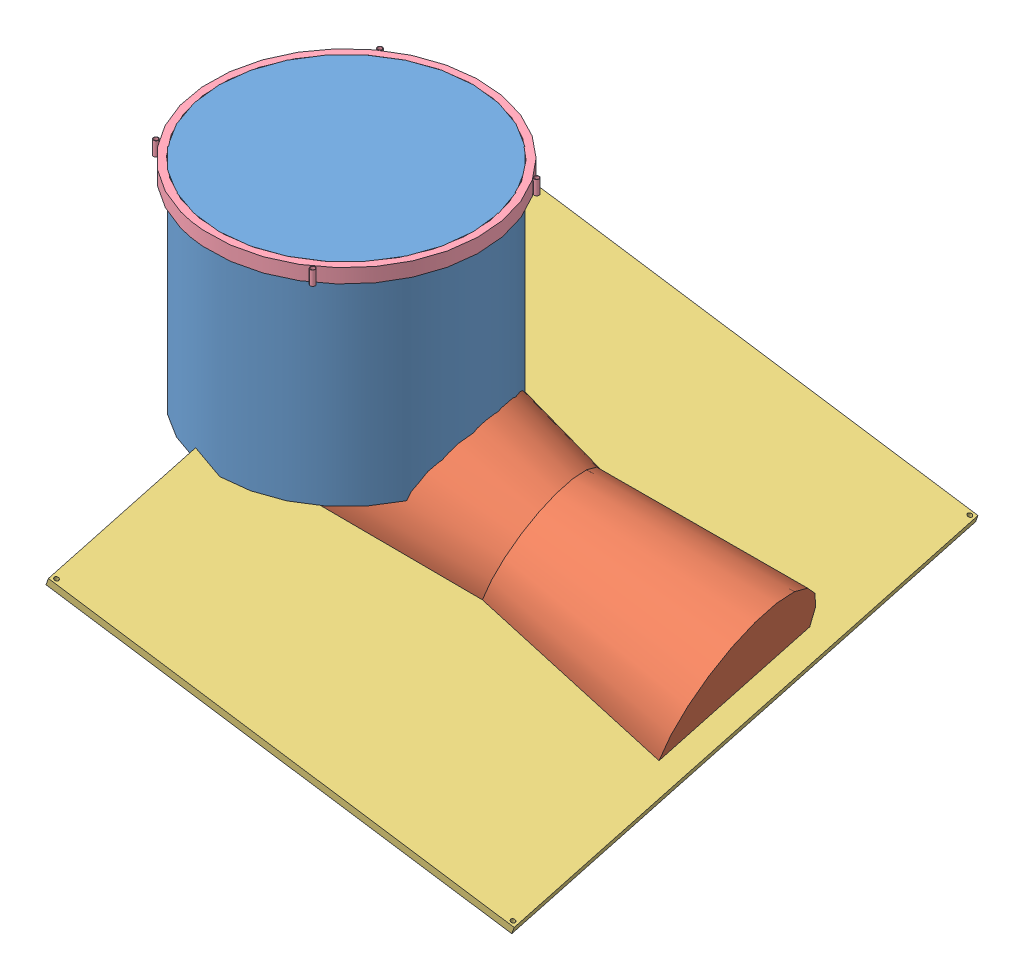
SolidWorks assembly Moving foot, configuration По умолчанию. Lengths in mm.
Overall size (389.71 306.49 446.02).
4 component instances, 4 part files, 13 mates.
Components (placement in the parent):
- Shank-1: Shank [По умолчанию] at origin size (180 150 180)
- foot-1: foot [По умолчанию] x (0.925259 -0.337269 -0.173626) z (0.164092 -0.05681 0.984808) size (320 70 140)
- foot platform-1: foot platform [По умолчанию] at (106.3356 -44.0525 -10.105) x (-0.925259 0.337269 0.173626) z (-0.164092 0.05681 -0.984808) size (300 5 400)
- Shank platform-1: Shank platform [По умолчанию] at (0 140 0) x (0.984808 0 0.173648) z (-0.173648 0 0.984808) size (190 10 190)
Mates (geometry in assembly coordinates):
- Концентричный1: concentric: sphere of Shank-1; sphere of foot-1
- Совпадение3: coincident anti-aligned: plane of foot-1 through (0 0 0) normal (-0.342009 -0.939693 0.00278); plane of foot platform-1 through (108.0457 -39.354 -10.1189) normal (0.342009 0.939693 -0.00278)
- Параллельность1: parallel aligned: plane of foot-1 through (241.9807 -88.0099 20.606) normal (0.925259 -0.337269 -0.173626); plane of foot platform-1 through (214.016 -78.5824 -233.1243) normal (0.925259 -0.337269 -0.173626)
- Расстояние1: distance = 15 mm aligned: plane of foot-1 through (241.9807 -88.0099 20.606) normal (0.925259 -0.337269 -0.173626); plane of foot platform-1 through (214.016 -78.5824 -233.1243) normal (0.925259 -0.337269 -0.173626)
- Расстояние3: distance = 145 mm: point of foot-1; line of foot platform-1 through (2.0754 -0.1256 212.8865) axis (0.925259 -0.337269 -0.173626)
- Граничный угол1: limit planar angle = 0.174533 rad aligned: plane of foot-1 through (0 0 0) normal (0.164092 -0.05681 0.984808); plane of Shank-1 through (0 0 0) normal (0 0 1)
- Граничный угол2: limit planar angle = 0.349066 rad aligned: plane of foot-1; plane of Shank-1 through (0 0 0) normal (0 1 0)
- Совпадение6: coincident aligned: plane of Shank-1 through (0 0 0) normal (1 0 0); plane of assembly through (0 0 0) normal (1 0 0)
- Совпадение7: coincident aligned: plane of Shank-1 through (0 0 0) normal (0 1 0); plane of assembly through (0 0 0) normal (0 1 0)
- Совпадение8: coincident aligned: plane of Shank-1 through (0 0 0) normal (1 0 0); plane of assembly through (0 0 0) normal (1 0 0)
- Совпадение9: coordinate: point of Shank-1; point of assembly
- Концентричный2: concentric aligned: cylinder of Shank-1 through (0 0 0) axis (0 -1 0) radius 90; cylinder of Shank platform-1 through (0 150 0) axis (0 -1 0) radius 90
- Совпадение10: coincident aligned: plane of Shank-1 through (0 150 0) normal (0 1 0); plane of Shank platform-1 through (0 150 0) normal (0 1 0)
